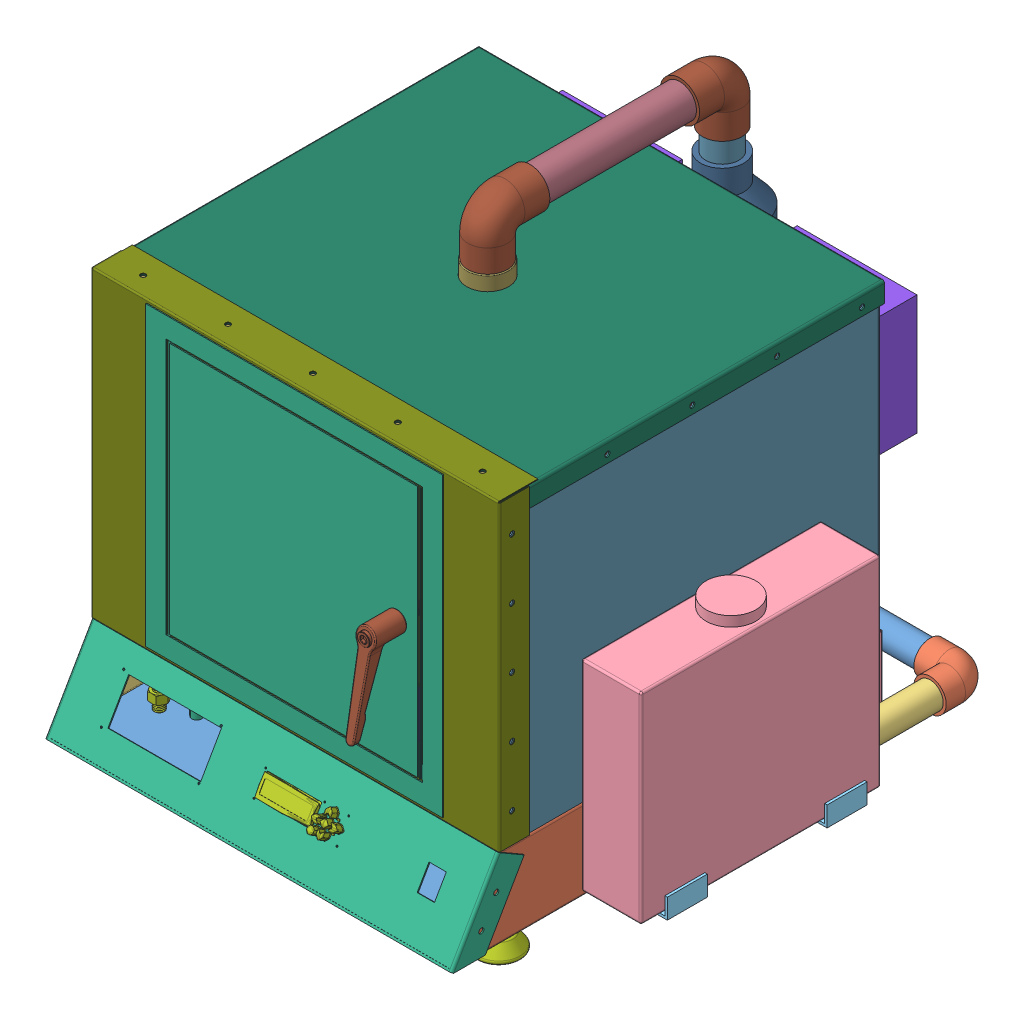
SolidWorks assembly Final_assembly, configuration Default. Lengths in mm.
Overall size (612.17 628.77 665.46).
71 component instances, 47 part files, 165 mates.
Components (placement in the parent):
- electrical_housing_bottom-1: electrical_housing_bottom [Default] at (213.7767 244.2924 441.0396) size (508 1.6 546.1)
- electrical_housing_right_side_base-1: electrical_housing_right_side_base [Default] at (470.9771 292.5603 407.2191) x (-1 0 0) z (0 0 -1) size (25.4 103.2 546.24)
- electrical_housing_left_side_base-1: electrical_housing_left_side_base [Default] at (-41.8235 292.5603 407.2191) x (-1 0 0) z (0 0 -1) size (25.4 103.2 546.24)
- electrical_housing_back-1: electrical_housing_back [Default] at (213.7767 294.2923 167.761) x (-1 0 0) z (0 0 -1) size (516.23 104.11 38.1)
- aluminum_main_base-1: aluminum_main_base [Default] at (213.7767 341.1426 412.3757) size (457.2 4.83 457.2)
- supports_bars-1: supports_bars [Default] at (397.9267 245.8926 596.5257) x (-0.271449 0 -0.962453) z (0.962453 0 -0.271449) size (12.7 95.25 12.7)
- supports_bars-2: supports_bars [Default] at (29.6267 245.8926 596.5257) x (-0.15787 0 -0.98746) z (0.98746 0 -0.15787) size (12.7 95.25 12.7)
- supports_bars-3: supports_bars [Default] at (29.6267 245.8926 228.2257) size (12.7 95.25 12.7)
- supports_bars-4: supports_bars [Default] at (397.9267 245.8926 228.2257) size (12.7 95.25 12.7)
- 60855K530_HVY DUTY VIBRATION-DAMPING LEVELING MOUNT-1: 60855K530_HVY DUTY VIBRATION-DAMPING LEVELING MOUNT [60855K53] at (429.6767 218.359 612.4896) x (-0.133468 0 -0.991053) z (0.991053 0 -0.133468) size (55.62 85.14 55.62)
- 60855K530_HVY DUTY VIBRATION-DAMPING LEVELING MOUNT-2: 60855K530_HVY DUTY VIBRATION-DAMPING LEVELING MOUNT [60855K53] at (-2.1233 218.359 612.4896) size (55.62 85.14 55.62)
- 60855K530_HVY DUTY VIBRATION-DAMPING LEVELING MOUNT-3: 60855K530_HVY DUTY VIBRATION-DAMPING LEVELING MOUNT [60855K53] at (-2.1233 218.359 218.7896) size (55.62 85.14 55.62)
- 60855K530_HVY DUTY VIBRATION-DAMPING LEVELING MOUNT-4: 60855K530_HVY DUTY VIBRATION-DAMPING LEVELING MOUNT [60855K53] at (429.6767 218.359 218.7896) size (55.62 85.14 55.62)
- bottom_stainless_steel-1: bottom_stainless_steel [Default] at (214.1196 345.8924 427.3109) size (511.89 25.4 446.1)
- 60855K530_HVY DUTY VIBRATION-DAMPING LEVELING MOUNT-5: 60855K530_HVY DUTY VIBRATION-DAMPING LEVELING MOUNT [60855K53] at (321.7267 218.359 415.6396) size (55.62 85.14 55.62)
- 60855K530_HVY DUTY VIBRATION-DAMPING LEVELING MOUNT-6: 60855K530_HVY DUTY VIBRATION-DAMPING LEVELING MOUNT [60855K53] at (105.8267 218.359 415.6396) size (55.62 85.14 55.62)
- back_wall-1: back_wall [Default] at (213.7767 537.3068 167.761) x (0 0 -1) z (1 0 0) size (1.6 381 508)
- back_wall_stainless_steel-1: back_wall_stainless_steel [Default] at (214.1196 537.3068 194.7612) size (463.49 381 25.4)
- side_wall_stainless_steel-3: side_wall_stainless_steel [Default] at (445.8642 537.3068 410.6612) size (0.91 381 479.4)
- side_wall_stainless_steel-4: side_wall_stainless_steel [Default] at (-18.5393 537.3068 410.6612) size (0.91 381 479.4)
- top_wall_stainless_steel-4: top_wall_stainless_steel [Default] at (214.1755 729.6356 421.761) x (1 0 0) z (0 0 -1) size (467.26 25.4 457.2)
- side_wall-2: side_wall [Default] at (-42.5093 537.3068 410.6612) x (-1 0 0) z (0 0 -1) size (50.8 381 485.8)
- side_wall_2-2: side_wall_2 [Default] at (469.3769 537.3068 410.6612) size (66.7 381 485.8)
- top_wall_aluminum-1: top_wall_aluminum [Default] at (213.7767 729.6356 407.4608) size (517.6 25.4 487.4)
- Front_wall_Door_opening-1: Front_wall_Door_opening [Default] at (213.7767 539.0213 654.4758) x (1 0 0) z (0 -1 0) size (519.43 50.8 385.34)
- Flange_bearing-2: Flange_bearing [Default] at (283.6267 331.8426 361.5757) x (0.999524 0 -0.030854) z (-0.030854 0 -0.999524) size (92.36 24 56)
- Flange_bearing-3: Flange_bearing [Default] at (143.9267 331.8426 361.5757) x (0.971318 0 0.237783) z (0.237783 0 -0.971318) size (92.36 24 56)
- half_in_diameter_one_inch_length_shafts-2: half_in_diameter_one_inch_length_shafts [Default] at (128.0652 355.2426 360.923) x (0.254336 0 -0.967116) z (0.967116 0 0.254336) size (12.7 50.8 12.7)
- half_in_diameter_one_inch_length_shafts-3: half_in_diameter_one_inch_length_shafts [Default] at (143.9267 317.1426 361.5757) x (0.692 0 -0.721898) z (0.721898 0 0.692) size (12.7 50.8 12.7)
- half_in_diameter_one_inch_length_shafts-4: half_in_diameter_one_inch_length_shafts [Default] at (267.7652 355.2426 360.923) size (12.7 50.8 12.7)
- half_in_diameter_one_inch_length_shafts-5: half_in_diameter_one_inch_length_shafts [Default] at (283.6267 317.1426 361.5757) size (12.7 50.8 12.7)
- half_in_diameter_one_inch_length_shafts-6: half_in_diameter_one_inch_length_shafts [Default] at (197.9152 355.2426 449.823) x (0.836358 0 -0.548183) z (0.548183 0 0.836358) size (12.7 50.8 12.7)
- link_circular-1: link_circular [Default] at (213.7767 355.2426 450.4757) x (-0.999154 0 -0.041115) z (0.041115 0 -0.999154) size (50.8 12.7 50.8)
- link_circular-2: link_circular [Default] at (283.6267 355.2426 361.5757) x (-0.999154 0 -0.041115) z (0.041115 0 -0.999154) size (50.8 12.7 50.8)
- link_circular-3: link_circular [Default] at (143.9267 355.2426 361.5757) x (-0.999154 0 -0.041115) z (0.041115 0 -0.999154) size (50.8 12.7 50.8)
- insert_bearing-1: insert_bearing [Default] at (128.0652 406.0426 360.923) x (0.968838 0 0.247697) z (0.247697 0 -0.968838) size (40 22 40)
- insert_bearing-2: insert_bearing [Default] at (197.9152 406.0426 449.823) x (1 0 0) z (0 0 -1) size (40 22 40)
- insert_bearing-3: insert_bearing [Default] at (267.7652 406.0426 360.923) x (0.361631 0 -0.932321) z (-0.932321 0 -0.361631) size (40 22 40)
- shaker_base-2: shaker_base [Default] at (197.9152 393.3426 405.373) x (-1 0 0) z (0 0 -1) size (203.2 12.7 152.4)
- Motor_w_shaft-1: Motor_w_shaft [Default] at (213.7767 312.4426 450.4757) x (-0.961699 0 0.274109) z (0 1 0) size (57 87.19 72.4)
- motor_shaft_connector-3: motor_shaft_connector [Default] at (213.7767 367.9426 450.4757) x (0.216668 0 -0.976245) z (-0.976245 0 -0.216668) size (28.51 24.8 28.51)
- user_interface_electrical_housing-1: user_interface_electrical_housing [Default] at (213.7767 294.2251 684.2866) x (1 0 0) z (0 0.499872 0.866099) size (517.6 119 38.1)
- platform-1: platform [Default] at (197.9152 406.0426 405.373) size (355.6 4.83 355.6)
- Humidity Blower-1: Humidity Blower [Default] at (213.7767 597.8858 112.1858) x (1 0 0) z (0 1 0) size (127 96.84 127)
- Heater w-bracket-1: Heater w-bracket [Default] at (366.1767 594.7108 166.1608) x (-1 0 0) z (0 0 -1) size (82.55 101.6 36.51)
- Heater w-bracket-3: Heater w-bracket [Default] at (61.3767 594.7108 166.1608) x (-1 0 0) z (0 0 -1) size (82.55 101.6 36.51)
- Coupling-1: Coupling [Default] at (213.7767 661.3858 112.1858) x (0.999912 0 0.013276) z (-0.013276 0 0.999912) size (100.45 95.25 100.45)
- Coupling-2: Coupling [Default] at (213.7767 534.3858 112.1858) x (-0.194845 0 0.980834) z (0.980834 0 0.194845) size (100.45 95.25 100.45)
- 4880K240_STANDARD-WALL WHITE PVC PIPE FITTING-1: 4880K240_STANDARD-WALL WHITE PVC PIPE FITTING [4880K24] at (213.7767 800.5778 112.1858) x (0 0 -1) z (-1 0 0) size (79.12 79.12 50.29)
- 4880K240_STANDARD-WALL WHITE PVC PIPE FITTING-2: 4880K240_STANDARD-WALL WHITE PVC PIPE FITTING [4880K24] at (213.7767 800.5778 410.6358) x (0 1 0) z (-1 0 0) size (79.12 79.12 50.29)
- 4881K234_THK-WALL DARK GRAY PVC UNTHRD PIPE FITTING-1: 4881K234_THK-WALL DARK GRAY PVC UNTHRD PIPE FITTING [4881K234] at (213.7767 711.2968 410.6358) x (0 0 -1) z (0 1 0) size (117.47 117.47 38.1)
- 48925K940_STANDARD-WALL WHITE PVC UNTHREADED PIPE-1: 48925K940_STANDARD-WALL WHITE PVC UNTHREADED PIPE [48925K94] at (213.7767 800.5778 261.4108) x (0.964332 -0.264695 0) z (0 0 1) size (42.16 42.16 254)
- PatchPipe3-1: PatchPipe3 [48925K94] at (213.7767 737.0778 112.1858) x (1 0 0) z (0 -1 0) size (42.16 42.16 82.55)
- PatchPipe1-2: PatchPipe1 [48925K94] at (213.7767 746.6028 410.6358) x (0.980543 0 0.196304) z (0 -1 0) size (42.16 42.16 63.5)
- PatchPipe2-1: PatchPipe2 [48925K94] at (213.7767 480.4108 112.1858) x (0.929723 0 -0.368261) z (0 -1 0) size (42.16 42.16 38.1)
- HumidifierEnclosure-1: HumidifierEnclosure [Default] at (251.8767 261.3358 80.4358) x (-1 0 0) z (0 0 -1) size (79.38 203.2 63.5)
- 48925K930_STANDARD-WALL WHITE PVC UNTHREADED PIPE-1: 48925K930_STANDARD-WALL WHITE PVC UNTHREADED PIPE [48925K93] at (213.7767 426.4358 166.1608) size (33.4 33.4 50.8)
- PatchPipe4-1: PatchPipe4 [48925K93] at (375.7017 293.0858 112.1858) x (0 0.029168 0.999575) z (1 0 0) size (33.4 33.4 254)
- 4880K230_STANDARD-WALL WHITE PVC PIPE FITTING-1: 4880K230_STANDARD-WALL WHITE PVC PIPE FITTING [4880K23] at (520.1642 293.0858 112.1858) x (1 0 0) z (0 -1 0) size (62.71 62.71 41.27)
- PatchPipe5-1: PatchPipe5 [48925K93] at (520.1642 293.0858 193.1483) x (0.999688 0.024976 0) z (0 0 -1) size (33.4 33.4 127)
- WaterReservoir-1: WaterReservoir [Default] at (558.2642 261.3358 559.8608) x (0 0 -1) z (1 0 0) size (304.8 268.29 76.2)
- Reservoir Hanger-1: Reservoir Hanger [Default] at (470.9771 258.1608 483.6608) size (95.25 38.1 50.8)
- Reservoir Hanger-2: Reservoir Hanger [Default] at (470.9771 258.1608 280.4608) size (95.25 38.1 50.8)
- Door - McM1369A11-1: Door - McM1369A11 [Default] at (53.4392 378.6838 617.2902) size (377.83 377.83 40.69)
- CFA533xxxKS-1: CFA533xxxKS [Default] at (259.7567 291.0039 684.3275) x (1 0.000001 0) z (0 0.499872 0.866099) size (113.01 63.17 40.1)
- Rear fan enclosure-1: Rear fan enclosure [Default] at (286.8271 508.9858 89.9608) size (152.4 152.4 76.2)
- Rear fan enclosure-2: Rear fan enclosure [Default] at (140.7263 508.9858 89.9608) x (0 1 0) z (0 0 1) size (152.4 152.4 76.2)
- PC FAN-1: PC FAN [Default] at (214.1196 600.8068 182.2612) x (-1 0 0) z (0 0 -1) size (160.61 160.57 33.39)
  - CPU Fan with no fan-1: CPU Fan with no fan [Default] at origin size (120 120 33.39)
  - FanBlade-1: FanBlade [Default] at (0 0 -9.5) x (-0.969943 0.243332 0) z (0 0 1) size (132.38 132.34 22)
- 64835K850_DIE CAST ZINC CONTEMPORARY STYLE ADJ HANDLE-1: 64835K850_DIE CAST ZINC CONTEMPORARY STYLE ADJ HANDLE [64835K85] at (344.8788 539.0213 624.1419) x (-1 0 0) z (0 0 1) size (25.4 124.77 114.45)
Mates (geometry in assembly coordinates):
- Coincident1: coincident: plane of electrical_housing_bottom-1 through (213.7767 244.2924 441.0396) normal (0 -1 0); plane of electrical_housing_right_side_base-1 through (470.9771 244.2924 407.2191) normal (0 1 0)
- Coincident2: coincident: plane of electrical_housing_bottom-1 through (467.7767 245.8926 714.0896) normal (1 0 0); line of electrical_housing_right_side_base-1 through (467.7767 244.2924 167.9896) axis (0 0 1)
- Coincident3: coincident: plane of electrical_housing_bottom-1 through (-40.2233 245.8926 167.9896) normal (0 0 -1); plane of electrical_housing_right_side_base-1 through (469.3769 242.6922 167.9896) normal (0 0 -1)
- Coincident4: coincident: plane of electrical_housing_bottom-1 through (-40.2233 245.8926 167.9896) normal (0 0 -1); plane of electrical_housing_left_side_base-1 through (-43.4237 242.6922 167.9896) normal (0 0 -1)
- Coincident5: coincident: plane of electrical_housing_bottom-1 through (213.7767 244.2924 441.0396) normal (0 -1 0); plane of electrical_housing_left_side_base-1 through (-41.8235 244.2924 407.2191) normal (0 1 0)
- Coincident6: coincident: plane of electrical_housing_bottom-1 through (-40.2233 245.8926 714.0896) normal (-1 0 0); line of electrical_housing_left_side_base-1 through (-40.2233 244.2924 714.029) axis (0 0 -1)
- Coincident9: coincident: plane of electrical_housing_right_side_base-1 through (470.9771 292.5603 407.2191) normal (1 0 0); plane of electrical_housing_back-1 through (470.9771 294.2923 167.761) normal (-1 0 0)
- Coincident10: coincident: plane of electrical_housing_right_side_base-1 through (469.3769 242.6922 167.9896) normal (0 0 -1); line of electrical_housing_back-1 through (470.9771 242.6922 167.9896) axis (0 1 0)
- Coincident11: coincident: plane of electrical_housing_right_side_base-1 through (470.9771 345.8924 407.2191) normal (0 1 0); plane of electrical_housing_back-1 through (213.7767 345.8924 167.761) normal (0 -1 0)
- Distance1: distance = 28.6004 mm: plane of aluminum_main_base-1 through (-14.8233 345.9686 640.9757) normal (-1 0 0); plane of electrical_housing_left_side_base-1 through (-43.4237 292.5603 407.2191) normal (-1 0 0)
- Concentric1: concentric: cylinder of aluminum_main_base-1 through (397.9267 340.8886 596.5257) axis (0 1 0) radius 3.175; cylinder of supports_bars-1 through (397.9267 341.1426 596.5257) axis (0 -1 0) radius 6.35
- Coincident13: coincident: plane of aluminum_main_base-1 through (213.7767 341.1426 412.3757) normal (0 -1 0); plane of supports_bars-1 through (397.9267 341.1426 596.5257) normal (0 1 0)
- Concentric2: concentric: cylinder of aluminum_main_base-1 through (29.6267 340.8886 596.5257) axis (0 1 0) radius 3.175; cylinder of supports_bars-2 through (29.6267 341.1426 596.5257) axis (0 -1 0) radius 6.35
- Coincident14: coincident: plane of aluminum_main_base-1 through (213.7767 341.1426 412.3757) normal (0 -1 0); plane of supports_bars-2 through (29.6267 341.1426 596.5257) normal (0 1 0)
- Concentric3: concentric: cylinder of aluminum_main_base-1 through (29.6267 340.8886 228.2257) axis (0 1 0) radius 3.175; cylinder of supports_bars-3 through (29.6267 341.1426 228.2257) axis (0 -1 0) radius 6.35
- Coincident15: coincident: plane of aluminum_main_base-1 through (213.7767 341.1426 412.3757) normal (0 -1 0); plane of supports_bars-3 through (29.6267 341.1426 228.2257) normal (0 1 0)
- Concentric4: concentric: cylinder of aluminum_main_base-1 through (397.9267 340.8886 228.2257) axis (0 1 0) radius 3.175; cylinder of supports_bars-4 through (397.9267 341.1426 228.2257) axis (0 -1 0) radius 6.35
- Coincident16: coincident: plane of aluminum_main_base-1 through (213.7767 341.1426 412.3757) normal (0 -1 0); plane of supports_bars-4 through (397.9267 341.1426 228.2257) normal (0 1 0)
- Coincident17: coincident: plane of electrical_housing_bottom-1 through (213.7767 245.8926 441.0396) normal (0 1 0); plane of supports_bars-1 through (397.9267 245.8926 596.5257) normal (0 -1 0)
- Tangent1: tangent: circle of electrical_housing_back-1; plane of aluminum_main_base-1 through (-14.8233 345.9686 183.7757) normal (0 0 -1)
- Coincident20: coincident: plane of electrical_housing_right_side_base-1 through (470.9771 242.6922 407.2191) normal (0 -1 0); plane of 60855K530_HVY DUTY VIBRATION-DAMPING LEVELING MOUNT-1 through (428.8877 242.6922 606.6307) normal (0 1 0)
- Concentric6: concentric: cylinder of electrical_housing_bottom-1 through (429.6767 243.3526 612.4896) axis (0 1 0) radius 6.35; circle of 60855K530_HVY DUTY VIBRATION-DAMPING LEVELING MOUNT-1
- Concentric7: concentric: cylinder of electrical_housing_bottom-1 through (-2.1233 243.3526 612.4896) axis (0 1 0) radius 6.35; circle of 60855K530_HVY DUTY VIBRATION-DAMPING LEVELING MOUNT-2
- Coincident21: coincident: plane of 60855K530_HVY DUTY VIBRATION-DAMPING LEVELING MOUNT-1 through (430.1005 281.859 615.6362) normal (0 1 0); plane of 60855K530_HVY DUTY VIBRATION-DAMPING LEVELING MOUNT-2 through (-5.2983 281.859 612.4896) normal (0 1 0)
- Concentric8: concentric: cylinder of electrical_housing_bottom-1 through (-2.1233 243.3526 218.7896) axis (0 1 0) radius 6.35; circle of 60855K530_HVY DUTY VIBRATION-DAMPING LEVELING MOUNT-3
- Coincident22: coincident: plane of 60855K530_HVY DUTY VIBRATION-DAMPING LEVELING MOUNT-2 through (-5.2983 281.859 612.4896) normal (0 1 0); plane of 60855K530_HVY DUTY VIBRATION-DAMPING LEVELING MOUNT-3 through (-5.2983 281.859 218.7896) normal (0 1 0)
- Concentric9: concentric: cylinder of electrical_housing_bottom-1 through (429.6767 243.3526 218.7896) axis (0 1 0) radius 6.35; circle of 60855K530_HVY DUTY VIBRATION-DAMPING LEVELING MOUNT-4
- Coincident23: coincident: plane of 60855K530_HVY DUTY VIBRATION-DAMPING LEVELING MOUNT-1 through (430.1005 281.859 615.6362) normal (0 1 0); plane of 60855K530_HVY DUTY VIBRATION-DAMPING LEVELING MOUNT-4 through (426.5017 281.859 218.7896) normal (0 1 0)
- Concentric10: concentric: cylinder of electrical_housing_bottom-1 through (321.7267 243.3526 415.6396) axis (0 1 0) radius 6.35; circle of 60855K530_HVY DUTY VIBRATION-DAMPING LEVELING MOUNT-5
- Concentric11: concentric: cylinder of electrical_housing_bottom-1 through (105.8267 243.3526 415.6396) axis (0 1 0) radius 6.35; circle of 60855K530_HVY DUTY VIBRATION-DAMPING LEVELING MOUNT-6
- Coincident27: coincident: plane of 60855K530_HVY DUTY VIBRATION-DAMPING LEVELING MOUNT-2 through (-5.2983 281.859 612.4896) normal (0 1 0); plane of 60855K530_HVY DUTY VIBRATION-DAMPING LEVELING MOUNT-6 through (102.6517 281.859 415.6396) normal (0 1 0)
- Coincident28: coincident: plane of 60855K530_HVY DUTY VIBRATION-DAMPING LEVELING MOUNT-1 through (430.1005 281.859 615.6362) normal (0 1 0); plane of 60855K530_HVY DUTY VIBRATION-DAMPING LEVELING MOUNT-5 through (318.5517 281.859 415.6396) normal (0 1 0)
- Coincident43: coincident: plane of electrical_housing_right_side_base-1 through (470.9771 345.8924 407.2191) normal (0 1 0); plane of bottom_stainless_steel-1 through (214.1196 345.8924 427.3109) normal (0 -1 0)
- Coincident52: coincident: plane of back_wall_stainless_steel-1 through (445.8642 537.3068 194.7612) normal (1 0 0); plane of side_wall_stainless_steel-3 through (445.8642 537.3068 410.6612) normal (-1 0 0)
- Concentric14: concentric: cylinder of back_wall_stainless_steel-1 through (-17.6249 689.7068 208.3756) axis (-1 0 0) radius 3.2639; cylinder of side_wall_stainless_steel-3 through (448.4042 689.7068 208.3756) axis (-1 0 0) radius 3.2639
- Coincident53: coincident: plane of back_wall_stainless_steel-1 through (-17.6249 537.3068 194.7612) normal (-1 0 0); plane of side_wall_stainless_steel-4 through (-17.6249 537.3068 410.6612) normal (1 0 0)
- Concentric15: concentric: cylinder of back_wall_stainless_steel-1 through (-17.6249 689.7068 208.3756) axis (-1 0 0) radius 3.2639; cylinder of side_wall_stainless_steel-4 through (-15.9993 689.7068 208.3756) axis (-1 0 0) radius 3.2639
- Coincident55: coincident: plane of side_wall_stainless_steel-4 through (-18.5393 537.3068 410.6612) normal (-1 0 0); plane of top_wall_stainless_steel-4 through (-18.5393 729.6356 421.761) normal (1 0 0)
- Coincident56: coincident: plane of side_wall_stainless_steel-3 through (446.7786 346.8068 650.361) normal (0 0 1); plane of top_wall_stainless_steel-4 through (447.8047 704.2356 650.361) normal (0 0 1)
- Coincident57: coincident: plane of side_wall_stainless_steel-3 through (446.7786 727.8068 650.361) normal (0 1 0); line of top_wall_stainless_steel-4 through (446.8903 727.8068 650.361) axis (1 0 0)
- Coincident58: coincident: plane of bottom_stainless_steel-1 through (214.1196 346.8068 427.3109) normal (0 1 0); plane of side_wall_stainless_steel-3 through (446.7786 346.8068 650.361) normal (0 -1 0)
- Coincident60: coincident: plane of bottom_stainless_steel-1 through (-40.9091 346.8068 650.361) normal (0 0 1); plane of side_wall_stainless_steel-4 through (-17.6249 346.8068 650.361) normal (0 0 1)
- Distance2: distance = 21.4554 mm: plane of side_wall_stainless_steel-4 through (-18.5393 537.3068 410.6612) normal (-1 0 0); line of bottom_stainless_steel-1 through (-39.9947 346.8068 650.361) axis (0 0 -1)
- Coincident61: coincident: plane of back_wall-1 through (213.7767 537.3068 167.761) normal (0 0 1); plane of side_wall-2 through (-42.5093 537.3068 167.761) normal (0 0 -1)
- Coincident62: coincident: plane of back_wall-1 through (-40.2233 346.8068 166.1608) normal (-1 0 0); line of side_wall-2 through (-40.2233 727.8068 167.761) axis (0 -1 0)
- Coincident63: coincident: plane of back_wall-1 through (467.7767 727.8068 166.1608) normal (0 1 0); plane of side_wall-2 through (-43.4237 727.8068 169.3612) normal (0 1 0)
- Coincident65: coincident: plane of electrical_housing_left_side_base-1 through (-43.4237 292.5603 407.2191) normal (-1 0 0); plane of side_wall-2 through (-43.4237 537.3068 410.6612) normal (-1 0 0)
- Coincident66: coincident: plane of bottom_stainless_steel-1 through (-41.8235 345.8924 427.3109) normal (-1 0 0); plane of side_wall-2 through (-41.8235 537.3068 410.6612) normal (1 0 0)
- Coincident67: coincident: plane of side_wall_stainless_steel-4 through (-17.6249 346.8068 650.361) normal (0 0 1); line of side_wall-2 through (-18.0237 727.8068 650.361) axis (0 -1 0)
- Coincident68: coincident: plane of side_wall-2 through (-43.4237 727.8068 169.3612) normal (0 1 0); plane of side_wall_2-2 through (469.3769 727.8068 651.9612) normal (0 1 0)
- Coincident69: coincident: plane of back_wall-1 through (213.7767 537.3068 167.761) normal (0 0 1); plane of side_wall_2-2 through (469.3769 537.3068 167.761) normal (0 0 -1)
- Coincident71: coincident: plane of back_wall-1 through (467.7767 346.8068 166.1608) normal (1 0 0); line of side_wall_2-2 through (467.7767 727.8068 169.3612) axis (0 0 -1)
- Coincident72: coincident: plane of back_wall_stainless_steel-1 through (214.1196 537.3068 194.7612) normal (0 0 -1); plane of side_wall_2-2 through (469.3769 537.3068 194.7612) normal (0 0 1)
- Coincident73: coincident: plane of side_wall-2 through (-43.4237 537.3068 410.6612) normal (-1 0 0); plane of top_wall_aluminum-1 through (-43.4237 729.6356 407.4608) normal (1 0 0)
- Coincident76: coincident: plane of back_wall-1 through (213.7767 537.3068 166.1608) normal (0 0 -1); line of top_wall_aluminum-1 through (469.3769 729.6356 166.1608) axis (-1 0 0)
- Coincident77: coincident: plane of top_wall_stainless_steel-4 through (214.1755 729.6356 421.761) normal (0 1 0); plane of top_wall_aluminum-1 through (213.7767 729.6356 407.4608) normal (0 -1 0)
- Coincident78: coincident: plane of top_wall_aluminum-1 through (213.7767 731.2358 407.4608) normal (0 1 0); plane of Front_wall_Door_opening-1 through (213.7767 731.2358 654.4758) normal (0 -1 0)
- Coincident79: coincident: plane of side_wall_2-2 through (469.3769 537.3068 653.5614) normal (0 0 1); line of Front_wall_Door_opening-1 through (472.5773 731.2358 653.5614) axis (0 -1 0)
- Parallel1: parallel: plane of side_wall-2 through (-42.5093 537.3068 653.5614) normal (0 0 1); plane of Front_wall_Door_opening-1 through (213.7767 539.0213 654.4758) normal (0 0 -1)
- Coincident80: coincident: plane of top_wall_aluminum-1 through (-45.0239 729.6356 407.4608) normal (-1 0 0); plane of Front_wall_Door_opening-1 through (-45.0239 539.0213 654.4758) normal (1 0 0)
- Concentric44: concentric: cylinder of aluminum_main_base-1 through (143.9267 320.5686 361.5757) axis (0 1 0) radius 7.62; cylinder of Flange_bearing-3 through (143.9267 317.1426 361.5757) axis (0 1 0) radius 6.35
- Concentric45: concentric: cylinder of aluminum_main_base-1 through (283.6267 320.5686 361.5757) axis (0 1 0) radius 7.62; cylinder of Flange_bearing-2 through (283.6267 317.1426 361.5757) axis (0 1 0) radius 6.35
- Coincident109: coincident: plane of aluminum_main_base-1 through (213.7767 341.1426 412.3757) normal (0 -1 0); plane of Flange_bearing-2 through (251.8919 341.1426 362.5553) normal (0 1 0)
- Coincident110: coincident: plane of aluminum_main_base-1 through (213.7767 341.1426 412.3757) normal (0 -1 0); plane of Flange_bearing-3 through (113.0874 341.1426 354.0261) normal (0 1 0)
- Concentric46: concentric: cylinder of Flange_bearing-2 through (283.6267 317.1426 361.5757) axis (0 1 0) radius 6.35; cylinder of half_in_diameter_one_inch_length_shafts-5 through (283.6267 367.9426 361.5757) axis (0 -1 0) radius 6.35
- Coincident111: coincident: plane of Flange_bearing-2 through (283.6267 317.1426 361.5757) normal (0 -1 0); plane of half_in_diameter_one_inch_length_shafts-5 through (283.6267 317.1426 361.5757) normal (0 -1 0)
- Concentric47: concentric: cylinder of Flange_bearing-3 through (143.9267 317.1426 361.5757) axis (0 1 0) radius 6.35; cylinder of half_in_diameter_one_inch_length_shafts-3 through (143.9267 367.9426 361.5757) axis (0 -1 0) radius 6.35
- Coincident112: coincident: plane of Flange_bearing-3 through (143.9267 317.1426 361.5757) normal (0 -1 0); plane of half_in_diameter_one_inch_length_shafts-3 through (143.9267 317.1426 361.5757) normal (0 -1 0)
- Concentric50: concentric: cylinder of half_in_diameter_one_inch_length_shafts-3 through (143.9267 367.9426 361.5757) axis (0 -1 0) radius 6.35; cylinder of link_circular-3 through (143.9267 355.2426 361.5757) axis (0 1 0) radius 6.35
- Coincident115: coincident: plane of half_in_diameter_one_inch_length_shafts-3 through (143.9267 367.9426 361.5757) normal (0 1 0); plane of link_circular-3 through (143.9267 367.9426 361.5757) normal (0 1 0)
- Concentric51: concentric: cylinder of half_in_diameter_one_inch_length_shafts-5 through (283.6267 367.9426 361.5757) axis (0 -1 0) radius 6.35; cylinder of link_circular-2 through (283.6267 355.2426 361.5757) axis (0 1 0) radius 6.35
- Coincident116: coincident: plane of half_in_diameter_one_inch_length_shafts-5 through (283.6267 367.9426 361.5757) normal (0 1 0); plane of link_circular-2 through (283.6267 367.9426 361.5757) normal (0 1 0)
- Concentric52: concentric: cylinder of half_in_diameter_one_inch_length_shafts-6 through (197.9152 406.0426 449.823) axis (0 -1 0) radius 6.35; cylinder of link_circular-1 through (197.9152 355.2426 449.823) axis (0 1 0) radius 6.35
- Coincident117: coincident: plane of half_in_diameter_one_inch_length_shafts-6 through (197.9152 355.2426 449.823) normal (0 -1 0); plane of link_circular-1 through (213.7767 355.2426 450.4757) normal (0 -1 0)
- Concentric53: concentric: cylinder of half_in_diameter_one_inch_length_shafts-2 through (128.0652 406.0426 360.923) axis (0 -1 0) radius 6.35; cylinder of link_circular-3 through (128.0652 355.2426 360.923) axis (0 1 0) radius 6.35
- Coincident118: coincident: plane of half_in_diameter_one_inch_length_shafts-2 through (128.0652 406.0426 360.923) normal (0 1 0); plane of half_in_diameter_one_inch_length_shafts-6 through (197.9152 406.0426 449.823) normal (0 1 0)
- Concentric54: concentric: cylinder of half_in_diameter_one_inch_length_shafts-4 through (267.7652 406.0426 360.923) axis (0 -1 0) radius 6.35; cylinder of link_circular-2 through (267.7652 355.2426 360.923) axis (0 1 0) radius 6.35
- Coincident119: coincident: plane of half_in_diameter_one_inch_length_shafts-4 through (267.7652 406.0426 360.923) normal (0 1 0); plane of half_in_diameter_one_inch_length_shafts-6 through (197.9152 406.0426 449.823) normal (0 1 0)
- Concentric55: concentric: cylinder of half_in_diameter_one_inch_length_shafts-6 through (197.9152 406.0426 449.823) axis (0 -1 0) radius 6.35; cylinder of insert_bearing-2 through (197.9152 384.0426 449.823) axis (0 1 0) radius 6.35
- Coincident120: coincident: plane of half_in_diameter_one_inch_length_shafts-6 through (197.9152 406.0426 449.823) normal (0 1 0); plane of insert_bearing-2 through (197.9152 406.0426 449.823) normal (0 1 0)
- Concentric56: concentric: cylinder of half_in_diameter_one_inch_length_shafts-4 through (267.7652 406.0426 360.923) axis (0 -1 0) radius 6.35; cylinder of insert_bearing-3 through (267.7652 384.0426 360.923) axis (0 1 0) radius 6.35
- Coincident121: coincident: plane of half_in_diameter_one_inch_length_shafts-4 through (267.7652 406.0426 360.923) normal (0 1 0); plane of insert_bearing-3 through (267.7652 406.0426 360.923) normal (0 1 0)
- Concentric57: concentric: cylinder of half_in_diameter_one_inch_length_shafts-2 through (128.0652 406.0426 360.923) axis (0 -1 0) radius 6.35; cylinder of insert_bearing-1 through (128.0652 384.0426 360.923) axis (0 1 0) radius 6.35
- Coincident122: coincident: plane of half_in_diameter_one_inch_length_shafts-2 through (128.0652 406.0426 360.923) normal (0 1 0); plane of insert_bearing-1 through (128.0652 406.0426 360.923) normal (0 1 0)
- Concentric58: concentric: cylinder of insert_bearing-2 through (197.9152 394.0426 449.823) axis (0 1 0) radius 20; cylinder of shaker_base-2 through (197.9152 393.3426 449.823) axis (0 1 0) radius 20
- Concentric59: concentric: cylinder of insert_bearing-1 through (128.0652 394.0426 360.923) axis (0 1 0) radius 20; cylinder of shaker_base-2 through (128.0652 393.3426 360.923) axis (0 1 0) radius 20
- Concentric60: concentric: cylinder of insert_bearing-3 through (267.7652 394.0426 360.923) axis (0 1 0) radius 20; cylinder of shaker_base-2 through (267.7652 393.3426 360.923) axis (0 1 0) radius 20
- Coincident123: coincident: plane of insert_bearing-3 through (267.7652 406.0426 360.923) normal (0 1 0); plane of shaker_base-2 through (197.9152 406.0426 405.373) normal (0 1 0)
- Coincident125: coincident: plane of aluminum_main_base-1 through (213.7767 341.1426 412.3757) normal (0 -1 0); plane of Motor_w_shaft-1 through (213.7767 341.1426 450.4757) normal (0 1 0)
- Concentric62: concentric: cylinder of aluminum_main_base-1 through (213.7767 320.5686 450.4757) axis (0 1 0) radius 6.35; cylinder of Motor_w_shaft-1 through (213.7767 289.3426 450.4757) axis (0 1 0) radius 3.175
- Coincident126: coincident: plane of half_in_diameter_one_inch_length_shafts-4 through (267.7652 355.2426 360.923) normal (0 -1 0); plane of link_circular-2 through (283.6267 355.2426 361.5757) normal (0 -1 0)
- Concentric63: concentric: cylinder of link_circular-1 through (213.7767 355.2426 450.4757) axis (0 1 0) radius 6.35; cylinder of Motor_w_shaft-1 through (213.7767 289.3426 450.4757) axis (0 1 0) radius 3.175
- Concentric64: concentric: cylinder of Motor_w_shaft-1 through (213.7767 289.3426 450.4757) axis (0 1 0) radius 3.175; cylinder of motor_shaft_connector-3 through (213.7767 361.7426 450.4757) axis (0 -1 0) radius 3.175
- Coincident127: coincident: plane of link_circular-1 through (213.7767 367.9426 450.4757) normal (0 1 0); plane of motor_shaft_connector-3 through (213.7767 367.9426 450.4757) normal (0 1 0)
- Coincident129: coincident: plane of electrical_housing_right_side_base-1 through (469.3769 242.6922 714.029) normal (0 0.499872 0.866099); plane of user_interface_electrical_housing-1 through (213.7767 294.2251 684.2866) normal (0 -0.499872 -0.866099)
- Coincident130: coincident: plane of electrical_housing_right_side_base-1 through (470.9771 292.5603 407.2191) normal (1 0 0); plane of user_interface_electrical_housing-1 through (470.9771 294.2251 684.2866) normal (-1 0 0)
- Coincident133: coincident: plane of shaker_base-2 through (197.9152 406.0426 405.373) normal (0 1 0); plane of platform-1 through (197.9152 406.0426 405.373) normal (0 -1 0)
- Distance3: distance = 101.6 mm: plane of platform-1 through (20.1152 410.8686 583.173) normal (0 0 1); plane of shaker_base-2 through (299.5152 406.0426 481.573) normal (0 0 1)
- Distance4: distance = 76.2 mm: plane of platform-1 through (375.7152 410.8686 583.173) normal (1 0 0); plane of shaker_base-2 through (299.5152 406.0426 329.173) normal (1 0 0)
- Coincident134: coincident: plane of back_wall-1 through (213.7767 537.3068 166.1608) normal (0 0 -1); plane of Humidity Blower-1 through (213.7767 597.8858 166.1608) normal (0 0 1)
- Coincident135: coincident: plane of back_wall-1 through (213.7767 537.3068 166.1608) normal (0 0 -1); plane of Heater w-bracket-1 through (366.1767 594.7108 166.1608) normal (0 0 1)
- Parallel2: parallel: plane of side_wall-2 through (-43.4237 537.3068 410.6612) normal (-1 0 0); plane of Heater w-bracket-1 through (324.9017 543.9108 164.5733) normal (-1 0 0)
- Width1: width: plane of side_wall_2-2 through (470.9771 537.3068 410.6612) normal (1 0 0); plane of side_wall-2 through (-43.4237 537.3068 410.6612) normal (-1 0 0); cylinder of Humidity Blower-1 through (213.7767 661.3858 112.1858) axis (0 -1 0) radius 42.8625
- Width2: width: plane of side_wall_2-2 through (470.9771 537.3068 410.6612) normal (1 0 0); plane of side_wall-2 through (-43.4237 537.3068 410.6612) normal (-1 0 0); plane of Heater w-bracket-3 through (20.1017 543.9108 164.5733) normal (-1 0 0); plane of Heater w-bracket-1 through (407.4517 543.9108 164.5733) normal (1 0 0)
- Distance5: distance = 101.6 mm: plane of top_wall_aluminum-1 through (213.7767 731.2358 407.4608) normal (0 1 0); plane of Heater w-bracket-1 through (390.783 629.6358 135.9983) normal (0 1 0)
- Concentric65: concentric: cylinder of Humidity Blower-1 through (213.7767 661.3858 112.1858) axis (0 -1 0) radius 42.8625; cylinder of Coupling-1 through (213.7767 623.2858 112.1858) axis (0 1 0) radius 42.926
- Coincident136: coincident: circle of Humidity Blower-1; plane of Coupling-1 through (213.7767 661.3858 112.1858) normal (0 -1 0)
- Distance7: distance = 12.7 mm: plane of Coupling-1 through (213.7767 718.5358 112.1858) normal (0 1 0); plane of top_wall_aluminum-1 through (213.7767 731.2358 407.4608) normal (0 1 0)
- Concentric66: concentric: cylinder of Humidity Blower-1 through (213.7767 661.3858 112.1858) axis (0 -1 0) radius 42.8625; cylinder of Coupling-2 through (213.7767 572.4858 112.1858) axis (0 -1 0) radius 42.926
- Coincident139: coincident: circle of Humidity Blower-1; plane of Coupling-2 through (213.7767 534.3858 112.1858) normal (0 1 0)
- Concentric67: concentric: cylinder of Coupling-1 through (213.7767 718.5358 112.1858) axis (0 -1 0) radius 21.082; cylinder of PatchPipe3-1 through (213.7767 695.8028 112.1858) axis (0 1 0) radius 21.082
- Concentric68: concentric: cone of 4880K240_STANDARD-WALL WHITE PVC PIPE FITTING-1 through (213.7767 746.6028 112.1858) axis (0 1 0); cylinder of PatchPipe3-1 through (213.7767 695.8028 112.1858) axis (0 1 0) radius 21.082
- Coincident140: coincident: plane of 4880K240_STANDARD-WALL WHITE PVC PIPE FITTING-1 through (213.7767 778.3528 112.1858) normal (0 -1 0); plane of PatchPipe3-1 through (213.7767 778.3528 112.1858) normal (0 1 0)
- Parallel3: parallel: plane of side_wall_2-2 through (470.9771 537.3068 410.6612) normal (1 0 0); plane of 4880K240_STANDARD-WALL WHITE PVC PIPE FITTING-1 through (213.7767 800.5778 112.1858) normal (-1 0 0)
- Distance8: distance = 28.067 mm: plane of 4880K240_STANDARD-WALL WHITE PVC PIPE FITTING-1 through (213.7767 746.6028 87.0398) normal (0 -1 0); plane of Coupling-1 through (213.7767 718.5358 112.1858) normal (0 1 0)
- Concentric69: concentric: cylinder of 4880K240_STANDARD-WALL WHITE PVC PIPE FITTING-1 through (213.7767 800.5778 134.4108) axis (0 0 -1) radius 5.9999; cylinder of 48925K940_STANDARD-WALL WHITE PVC UNTHREADED PIPE-1 through (213.7767 800.5778 388.4108) axis (0 0 -1) radius 21.082
- Coincident142: coincident: plane of 4880K240_STANDARD-WALL WHITE PVC PIPE FITTING-1 through (213.7767 800.5778 134.4108) normal (0 0 1); plane of 48925K940_STANDARD-WALL WHITE PVC UNTHREADED PIPE-1 through (213.7767 800.5778 134.4108) normal (0 0 -1)
- Concentric70: concentric: cylinder of 4880K240_STANDARD-WALL WHITE PVC PIPE FITTING-2 through (213.7767 800.5778 356.6608) axis (0 0 1) radius 5.9999; cylinder of 48925K940_STANDARD-WALL WHITE PVC UNTHREADED PIPE-1 through (213.7767 800.5778 388.4108) axis (0 0 -1) radius 21.082
- Coincident143: coincident: plane of 4880K240_STANDARD-WALL WHITE PVC PIPE FITTING-2 through (213.7767 800.5778 388.4108) normal (0 0 -1); plane of 48925K940_STANDARD-WALL WHITE PVC UNTHREADED PIPE-1 through (213.7767 800.5778 388.4108) normal (0 0 1)
- Parallel4: parallel: plane of top_wall_aluminum-1 through (213.7767 731.2358 407.4608) normal (0 1 0); plane of 4880K240_STANDARD-WALL WHITE PVC PIPE FITTING-2 through (213.7767 746.6028 435.7818) normal (0 -1 0)
- Concentric71: concentric: cylinder of 4880K240_STANDARD-WALL WHITE PVC PIPE FITTING-2 through (213.7767 778.3528 410.6358) axis (0 1 0) radius 5.9999; cylinder of PatchPipe1-2 through (213.7767 714.8528 410.6358) axis (0 1 0) radius 21.082
- Coincident145: coincident: plane of 4880K240_STANDARD-WALL WHITE PVC PIPE FITTING-2 through (213.7767 778.3528 410.6358) normal (0 -1 0); plane of PatchPipe1-2 through (213.7767 778.3528 410.6358) normal (0 1 0)
- Concentric72: concentric: cylinder of 4881K234_THK-WALL DARK GRAY PVC UNTHRD PIPE FITTING-1 through (213.7767 749.3968 410.6358) axis (0 -1 0) radius 5.5146; cylinder of PatchPipe1-2 through (213.7767 714.8528 410.6358) axis (0 1 0) radius 21.082
- Coincident146: coincident: plane of 4881K234_THK-WALL DARK GRAY PVC UNTHRD PIPE FITTING-1 through (196.5047 714.8528 410.6358) normal (0 1 0); plane of PatchPipe1-2 through (213.7767 714.8528 410.6358) normal (0 -1 0)
- Parallel5: parallel: plane of top_wall_stainless_steel-4 through (447.8047 729.6356 421.761) normal (1 0 0); plane of 4881K234_THK-WALL DARK GRAY PVC UNTHRD PIPE FITTING-1 through (213.7767 711.2968 410.6358) normal (-1 0 0)
- Concentric73: concentric: cylinder of Coupling-2 through (213.7767 477.2358 112.1858) axis (0 1 0) radius 21.082; cylinder of PatchPipe2-1 through (213.7767 461.3608 112.1858) axis (0 1 0) radius 21.082
- Concentric74: concentric: cylinder of PatchPipe2-1 through (213.7767 461.3608 112.1858) axis (0 1 0) radius 21.082; cylinder of HumidifierEnclosure-1 through (213.7767 261.3348 112.1858) axis (0 1 0) radius 21.082
- Coincident148: coincident: plane of PatchPipe2-1 through (213.7767 461.3608 112.1858) normal (0 -1 0); circle of HumidifierEnclosure-1
- Parallel6: parallel: plane of back_wall-1 through (213.7767 537.3068 166.1608) normal (0 0 -1); plane of HumidifierEnclosure-1 through (251.8767 464.5358 143.9358) normal (0 0 1)
- Distance9: distance = 12.7 mm: plane of Coupling-2 through (213.7767 477.2358 112.1858) normal (0 -1 0); plane of HumidifierEnclosure-1 through (251.8767 464.5358 80.4358) normal (0 1 0)
- Concentric77: concentric: cylinder of HumidifierEnclosure-1 through (213.7767 426.4358 80.4348) axis (0 0 1) radius 16.764; cylinder of 48925K930_STANDARD-WALL WHITE PVC UNTHREADED PIPE-1 through (213.7767 426.4358 191.5608) axis (0 0 -1) radius 16.7005
- Coincident151: coincident: plane of HumidifierEnclosure-1 through (251.8767 464.5358 140.7608) normal (0 0 -1); plane of 48925K930_STANDARD-WALL WHITE PVC UNTHREADED PIPE-1 through (213.7767 426.4358 140.7608) normal (0 0 -1)
- Concentric78: concentric: cylinder of HumidifierEnclosure-1 through (175.6757 293.0858 112.1858) axis (1 0 0) radius 16.764; cylinder of PatchPipe4-1 through (502.7017 293.0858 112.1858) axis (-1 0 0) radius 16.7005
- Coincident152: coincident: plane of HumidifierEnclosure-1 through (248.7017 464.5358 80.4358) normal (-1 0 0); plane of PatchPipe4-1 through (248.7017 293.0858 112.1858) normal (-1 0 0)
- Concentric79: concentric: cylinder of PatchPipe4-1 through (502.7017 293.0858 112.1858) axis (-1 0 0) radius 16.7005; cylinder of 4880K230_STANDARD-WALL WHITE PVC PIPE FITTING-1 through (502.7017 293.0858 112.1858) axis (1 0 0) radius 7.7418
- Coincident153: coincident: plane of PatchPipe4-1 through (502.7017 293.0858 112.1858) normal (1 0 0); plane of 4880K230_STANDARD-WALL WHITE PVC PIPE FITTING-1 through (502.7017 293.0858 112.1858) normal (-1 0 0)
- Concentric80: concentric: cylinder of 4880K230_STANDARD-WALL WHITE PVC PIPE FITTING-1 through (520.1642 293.0858 154.2546) axis (0 0 -1) radius 7.7418; cylinder of PatchPipe5-1 through (520.1642 293.0858 129.6483) axis (0 0 1) radius 16.7005
- Coincident154: coincident: plane of 4880K230_STANDARD-WALL WHITE PVC PIPE FITTING-1 through (520.1642 293.0858 129.6483) normal (0 0 1); plane of PatchPipe5-1 through (520.1642 293.0858 129.6483) normal (0 0 -1)
- Concentric81: concentric: cylinder of PatchPipe5-1 through (520.1642 293.0858 129.6483) axis (0 0 1) radius 16.7005; cylinder of WaterReservoir-1 through (520.1642 293.0858 559.8618) axis (0 0 -1) radius 16.764
- Parallel7: parallel: plane of electrical_housing_bottom-1 through (213.7767 244.2924 441.0396) normal (0 -1 0); plane of WaterReservoir-1 through (558.2642 261.3358 559.8608) normal (0 -1 0)
- Coincident156: coincident: plane of PatchPipe5-1 through (520.1642 293.0858 256.6483) normal (0 0 1); circle of WaterReservoir-1
- Coincident157: coincident: plane of electrical_housing_right_side_base-1 through (470.9771 292.5603 407.2191) normal (1 0 0); plane of Reservoir Hanger-1 through (470.9771 258.1608 534.4608) normal (-1 0 0)
- Coincident158: coincident: plane of WaterReservoir-1 through (558.2642 261.3358 559.8608) normal (0 -1 0); plane of Reservoir Hanger-1 through (474.1521 261.3358 534.4608) normal (0 1 0)
- Distance10: distance = 25.4 mm: plane of Reservoir Hanger-1 through (470.9771 258.1608 534.4608) normal (0 0 1); plane of WaterReservoir-1 through (558.2642 515.3358 559.8608) normal (0 0 1)
- Coincident160: coincident: plane of Reservoir Hanger-1 through (566.2271 258.1608 534.4608) normal (0 -1 0); plane of Reservoir Hanger-2 through (566.2271 258.1608 331.2608) normal (0 -1 0)
- Coincident161: coincident: plane of electrical_housing_right_side_base-1 through (470.9771 292.5603 407.2191) normal (1 0 0); plane of Reservoir Hanger-2 through (470.9771 258.1608 331.2608) normal (-1 0 0)
- Distance11: distance = 25.4 mm: plane of WaterReservoir-1 through (558.2642 515.3358 255.0608) normal (0 0 -1); plane of Reservoir Hanger-2 through (470.9771 258.1608 280.4608) normal (0 0 -1)
- Width3: width: plane of Front_wall_Door_opening-1 through (374.1142 378.6838 654.4758) normal (-1 0 0); plane of Front_wall_Door_opening-1 through (53.4392 378.6838 654.4758) normal (1 0 0); plane of Door - McM1369A11-1 through (375.4096 377.3884 655.3902) normal (1 0 0); plane of Door - McM1369A11-1 through (52.1438 377.3884 655.3902) normal (-1 0 0)
- Width4: width: plane of Front_wall_Door_opening-1 through (53.4392 378.6838 654.4758) normal (0 1 0); plane of Front_wall_Door_opening-1 through (53.4392 699.3588 654.4758) normal (0 -1 0); plane of Door - McM1369A11-1 through (52.1438 377.3884 655.3902) normal (0 -1 0); plane of Door - McM1369A11-1 through (52.1438 700.6542 655.3902) normal (0 1 0)
- Coincident163: coincident: plane of Front_wall_Door_opening-1 through (213.7767 539.0213 655.3902) normal (0 0 1); plane of Door - McM1369A11-1 through (53.4392 378.6838 655.3902) normal (0 0 -1)
- Distance12: distance = 3.175 mm: plane of CFA533xxxKS-1 through (259.7567 291.0039 684.3275) normal (0 0.499872 0.866099); plane of user_interface_electrical_housing-1 through (213.7767 295.025 685.6725) normal (0 0.499872 0.866099)
- Tangent4: tangent: cylinder of user_interface_electrical_housing-1 through (196.8487 284.6402 688.7335) axis (0 0.499872 0.866099) radius 1.0795; face of CFA533xxxKS-1
- Tangent5: tangent: cylinder of user_interface_electrical_housing-1 through (302.3489 310.6232 673.7373) axis (0 0.499872 0.866099) radius 1.0795; edge_curve of CFA533xxxKS-1
- Coincident164: coincident: plane of electrical_housing_right_side_base-1 through (470.9771 242.6922 407.2191) normal (0 -1 0); line of user_interface_electrical_housing-1 through (-41.8235 242.6922 714.029) axis (1 0 0)
- Coincident165: coincident: plane of back_wall-1 through (213.7767 537.3068 166.1608) normal (0 0 -1); plane of Rear fan enclosure-2 through (140.7263 508.9858 166.1608) normal (0 0 1)
- Distance13: distance = 69.85 mm: plane of Rear fan enclosure-2 through (140.7263 661.3858 166.1608) normal (0 1 0); plane of top_wall_aluminum-1 through (213.7767 731.2358 407.4608) normal (0 1 0)
- Distance14: distance = 31.75 mm: plane of Rear fan enclosure-2 through (-11.6737 508.9858 166.1608) normal (-1 0 0); plane of side_wall-2 through (-43.4237 537.3068 410.6612) normal (-1 0 0)
- Coincident168: coincident: plane of back_wall-1 through (213.7767 537.3068 166.1608) normal (0 0 -1); plane of Rear fan enclosure-1 through (286.8271 508.9858 166.1608) normal (0 0 1)
- Coincident169: coincident: plane of Rear fan enclosure-1 through (286.8271 661.3858 166.1608) normal (0 1 0); plane of Rear fan enclosure-2 through (140.7263 661.3858 166.1608) normal (0 1 0)
- Distance15: distance = 31.75 mm: plane of Rear fan enclosure-1 through (439.2271 508.9858 166.1608) normal (1 0 0); plane of side_wall_2-2 through (470.9771 537.3068 410.6612) normal (1 0 0)
- Coincident171: coincident: circle of back_wall_stainless_steel-1; plane of PC FAN-1/CPU Fan with no fan-1 through (269.6196 545.3068 194.7612) normal (0 0 1)
- Concentric85: concentric: cylinder of back_wall_stainless_steel-1 through (214.1196 600.8068 194.7612) axis (0 0 1) radius 57.15; cylinder of PC FAN-1/CPU Fan with no fan-1 through (214.1196 600.8068 191.7612) axis (0 0 1) radius 16.3
- Concentric86: concentric: circle of Door - McM1369A11-1; cylinder of 64835K850_DIE CAST ZINC CONTEMPORARY STYLE ADJ HANDLE-1 through (344.8788 539.0213 604.2981) axis (0 0 -1) radius 12.7
- Coincident172: coincident: plane of Door - McM1369A11-1 through (53.4392 378.6838 656.6856) normal (0 0 1); plane of 64835K850_DIE CAST ZINC CONTEMPORARY STYLE ADJ HANDLE-1 through (344.8788 529.4963 656.6856) normal (0 0 -1)
- Parallel10: parallel: plane of Front_wall_Door_opening-1 through (473.4917 539.0213 654.4758) normal (1 0 0); plane of 64835K850_DIE CAST ZINC CONTEMPORARY STYLE ADJ HANDLE-1 through (340.9101 541.3127 695.8364) normal (1 0 0)
